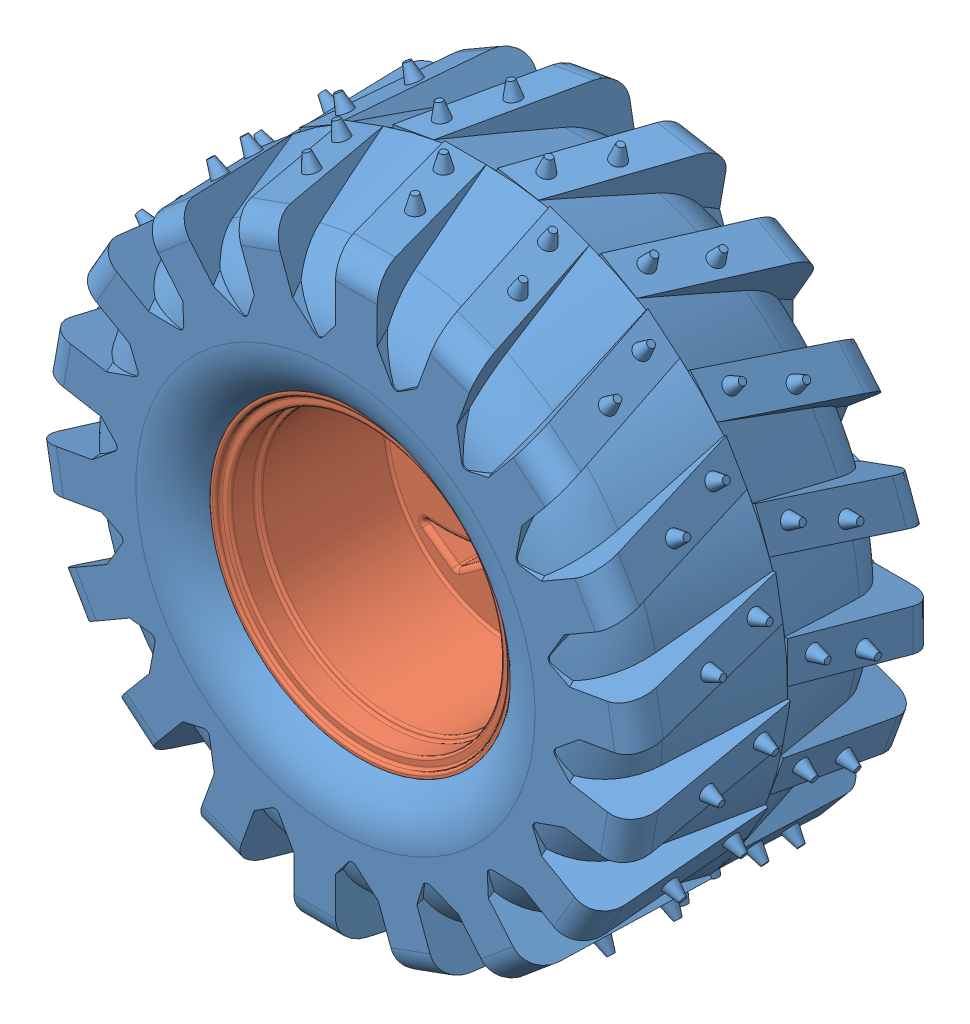
SolidWorks assembly left_wheel_asm, configuration Default. Lengths in mm.
Overall size (126 126 64.53).
5 component instances, 5 part files, 9 mates.
Components (placement in the parent):
- Tire-1: Tire [Varsayılan] at (37.7234 65.1994 132.8068) size (126 126 62.61)
- tire_rim-1: tire_rim [Varsayılan] at (30.4723 64.8451 82.8068) x (0.823515 -0.567294 0) z (0 0 1) size (60 60 50)
- wheel_adapter-1: wheel_adapter [Default] at (22.8801 68.188 91.8068) x (0.504749 -0.863266 0) z (0.863266 0.504749 0) size (12.7 16 11)
- m4_12mm_allen-1: m4_12mm_allen [Default] at (22.8801 68.188 89.8068) x (0.29141 0.956598 0) z (0.956598 -0.29141 0) size (8 16 8)
- m3_8mm_allen-1: m3_8mm_allen [Default] at (21.1535 67.1785 78.637) x (-0.446065 0.762898 0.467988) z (0.236217 -0.403998 0.883735) size (6 11 6)
Mates (geometry in assembly coordinates):
- Concentric1: concentric: cylinder of Tire-1 through (22.8801 68.188 112.8068) axis (0 0 1) radius 30; cylinder of tire_rim-1 through (22.8801 68.188 132.8068) axis (0 0 -1) radius 30
- Coincident1: coincident: circle of Tire-1; circle of tire_rim-1
- Coincident2: coincident: plane of tire_rim-1 through (30.4723 64.8451 91.8068) normal (0 0 -1); plane of wheel_adapter-1 through (22.8801 68.188 91.8068) normal (0 0 1)
- Coincident3: coincident: plane of tire_rim-1 through (26.0856 62.7056 83.8068) normal (-0.005493 0.999985 0); plane of wheel_adapter-1 through (26.0856 62.7056 89.8068) normal (0.005493 -0.999985 0)
- Coincident4: coincident: plane of tire_rim-1 through (19.7349 62.6707 83.8068) normal (0.863266 0.504749 0); plane of wheel_adapter-1 through (19.7349 62.6707 89.8068) normal (-0.863266 -0.504749 0)
- Concentric2: concentric: cylinder of tire_rim-1 through (22.8801 68.188 82.8068) axis (0 0 1) radius 2; cylinder of m4_12mm_allen-1 through (22.8801 68.188 101.8068) axis (0 0 -1) radius 2
- Coincident5: coincident: plane of tire_rim-1 through (22.8801 68.188 101.8068) normal (0 0 1); plane of m4_12mm_allen-1 through (22.8801 68.188 101.8068) normal (0 0 -1)
- Concentric3: concentric: cylinder of wheel_adapter-1 through (12.5209 62.131 80.637) axis (0.863266 0.504749 0) radius 1.5; cylinder of m3_8mm_allen-1 through (14.8319 63.4823 80.637) axis (0.863266 0.504749 0) radius 1.5
- Tangent2: tangent: curve of wheel_adapter-1; circle of m3_8mm_allen-1
